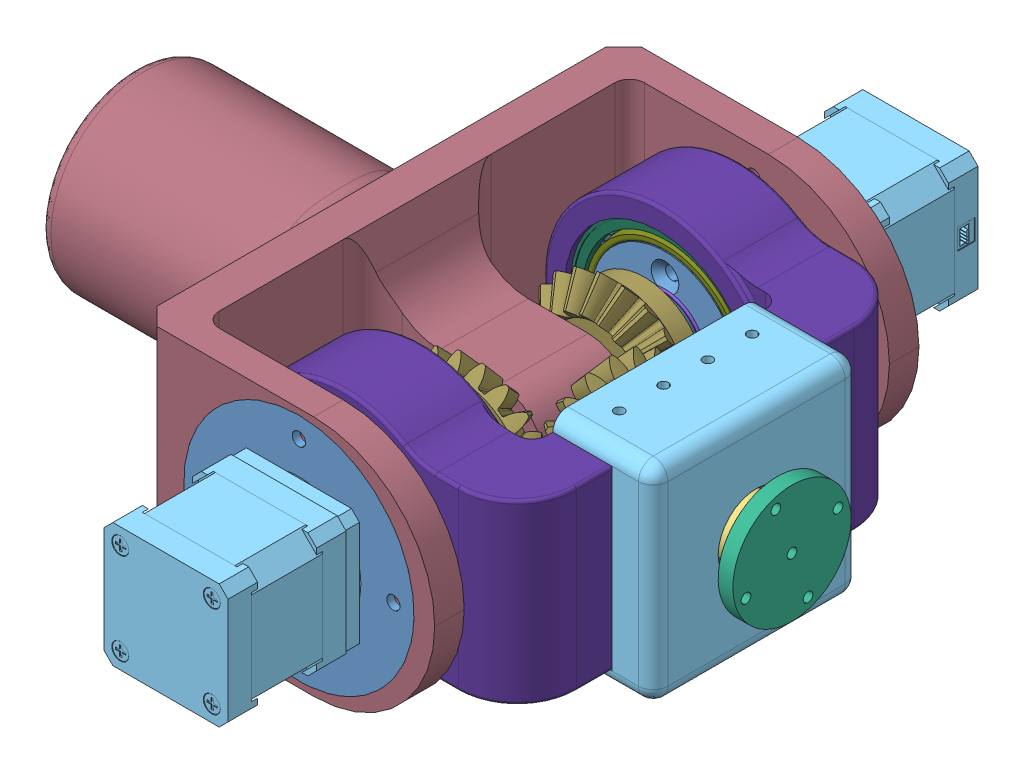
SolidWorks assembly Wrist assembly v3, configuration Default. Lengths in mm.
Overall size (223 82 254).
259 component instances, 28 part files, 61 mates.
Components (placement in the parent):
- Motor sleeve-1: Motor sleeve [Default] at (57.5488 50.2907 113.4481) x (0 0 -1) z (1 0 0) size (40 78 78)
- Motor sleeve-2: Motor sleeve [Default] at (57.5488 50.2907 -50.5519) x (0 0 1) z (-1 0 0) size (40 78 78)
- HK_1412-1: HK_1412 [Default] at (57.5488 50.2907 46.4481) x (0 0 -1) z (0.911021 -0.412359 0) size (12 20 20)
  - HK_1412_3-1: HK_1412_3 [Default] x (1 0 0) z (0 -0.382683 0.92388) size (7.3 2 2)
  - HK_1412_3-2: HK_1412_3 [Default] x (1 0 0) z (0 -0.707107 0.707107) size (7.3 2 2)
  - HK_1412_3-3: HK_1412_3 [Default] x (1 0 0) z (0 -0.92388 0.382683) size (7.3 2 2)
  - HK_1412_3-4: HK_1412_3 [Default] x (1 0 0) z (0 -1 0) size (7.3 2 2)
  - HK_1412_3-5: HK_1412_3 [Default] x (1 0 0) z (0 -0.92388 -0.382683) size (7.3 2 2)
  - HK_1412_3-6: HK_1412_3 [Default] x (1 0 0) z (0 -0.707107 -0.707107) size (7.3 2 2)
  - HK_1412_3-7: HK_1412_3 [Default] x (1 0 0) z (0 -0.382683 -0.92388) size (7.3 2 2)
  - HK_1412_3-8: HK_1412_3 [Default] x (1 0 0) z (0 0 -1) size (7.3 2 2)
  - HK_1412_3-9: HK_1412_3 [Default] x (1 0 0) z (0 0.382683 -0.92388) size (7.3 2 2)
  - HK_1412_3-10: HK_1412_3 [Default] x (1 0 0) z (0 0.707107 -0.707107) size (7.3 2 2)
  - HK_1412_3-11: HK_1412_3 [Default] x (1 0 0) z (0 0.92388 -0.382683) size (7.3 2 2)
  - HK_1412_3-12: HK_1412_3 [Default] x (1 0 0) z (0 1 0) size (7.3 2 2)
  - HK_1412_3-13: HK_1412_3 [Default] x (1 0 0) z (0 0.92388 0.382683) size (7.3 2 2)
  - HK_1412_3-14: HK_1412_3 [Default] x (1 0 0) z (0 0.707107 0.707107) size (7.3 2 2)
  - HK_1412_3-15: HK_1412_3 [Default] x (1 0 0) z (0 0.382683 0.92388) size (7.3 2 2)
  - HK_1412_3-16: HK_1412_3 [Default] at origin size (7.3 2 2)
  - HK_1412_20-1: HK_1412_20 [Default] x (1 0 0) z (0 -0.382683 0.92388) size (7.3 2 2)
  - HK_1412_20-2: HK_1412_20 [Default] x (1 0 0) z (0 -0.707107 0.707107) size (7.3 2 2)
  - HK_1412_20-3: HK_1412_20 [Default] x (1 0 0) z (0 -0.92388 0.382683) size (7.3 2 2)
  - HK_1412_20-4: HK_1412_20 [Default] x (1 0 0) z (0 -1 0) size (7.3 2 2)
  - HK_1412_20-5: HK_1412_20 [Default] x (1 0 0) z (0 -0.92388 -0.382683) size (7.3 2 2)
  - HK_1412_20-6: HK_1412_20 [Default] x (1 0 0) z (0 -0.707107 -0.707107) size (7.3 2 2)
  - HK_1412_20-7: HK_1412_20 [Default] x (1 0 0) z (0 -0.382683 -0.92388) size (7.3 2 2)
  - HK_1412_20-8: HK_1412_20 [Default] x (1 0 0) z (0 0 -1) size (7.3 2 2)
  - HK_1412_20-9: HK_1412_20 [Default] x (1 0 0) z (0 0.382683 -0.92388) size (7.3 2 2)
  - HK_1412_20-10: HK_1412_20 [Default] x (1 0 0) z (0 0.707107 -0.707107) size (7.3 2 2)
  - HK_1412_20-11: HK_1412_20 [Default] x (1 0 0) z (0 0.92388 -0.382683) size (7.3 2 2)
  - HK_1412_20-12: HK_1412_20 [Default] x (1 0 0) z (0 1 0) size (7.3 2 2)
  - HK_1412_20-13: HK_1412_20 [Default] x (1 0 0) z (0 0.92388 0.382683) size (7.3 2 2)
  - HK_1412_20-14: HK_1412_20 [Default] x (1 0 0) z (0 0.707107 0.707107) size (7.3 2 2)
  - HK_1412_20-15: HK_1412_20 [Default] x (1 0 0) z (0 0.382683 0.92388) size (7.3 2 2)
  - HK_1412_20-16: HK_1412_20 [Default] at origin size (7.3 2 2)
  - HK_1412_37-1: HK_1412_37 [Default] at origin size (12 20 20)
- HK_1412-2: HK_1412 [Default] at (57.5488 50.2907 28.4481) x (0 0 -1) z (0.122911 0.992418 0) size (12 20 20)
  - HK_1412_3-1: HK_1412_3 [Default] x (1 0 0) z (0 -0.382683 0.92388) size (7.3 2 2)
  - HK_1412_3-2: HK_1412_3 [Default] x (1 0 0) z (0 -0.707107 0.707107) size (7.3 2 2)
  - HK_1412_3-3: HK_1412_3 [Default] x (1 0 0) z (0 -0.92388 0.382683) size (7.3 2 2)
  - HK_1412_3-4: HK_1412_3 [Default] x (1 0 0) z (0 -1 0) size (7.3 2 2)
  - HK_1412_3-5: HK_1412_3 [Default] x (1 0 0) z (0 -0.92388 -0.382683) size (7.3 2 2)
  - HK_1412_3-6: HK_1412_3 [Default] x (1 0 0) z (0 -0.707107 -0.707107) size (7.3 2 2)
  - HK_1412_3-7: HK_1412_3 [Default] x (1 0 0) z (0 -0.382683 -0.92388) size (7.3 2 2)
  - HK_1412_3-8: HK_1412_3 [Default] x (1 0 0) z (0 0 -1) size (7.3 2 2)
  - HK_1412_3-9: HK_1412_3 [Default] x (1 0 0) z (0 0.382683 -0.92388) size (7.3 2 2)
  - HK_1412_3-10: HK_1412_3 [Default] x (1 0 0) z (0 0.707107 -0.707107) size (7.3 2 2)
  - HK_1412_3-11: HK_1412_3 [Default] x (1 0 0) z (0 0.92388 -0.382683) size (7.3 2 2)
  - HK_1412_3-12: HK_1412_3 [Default] x (1 0 0) z (0 1 0) size (7.3 2 2)
  - HK_1412_3-13: HK_1412_3 [Default] x (1 0 0) z (0 0.92388 0.382683) size (7.3 2 2)
  - HK_1412_3-14: HK_1412_3 [Default] x (1 0 0) z (0 0.707107 0.707107) size (7.3 2 2)
  - HK_1412_3-15: HK_1412_3 [Default] x (1 0 0) z (0 0.382683 0.92388) size (7.3 2 2)
  - HK_1412_3-16: HK_1412_3 [Default] at origin size (7.3 2 2)
  - HK_1412_20-1: HK_1412_20 [Default] x (1 0 0) z (0 -0.382683 0.92388) size (7.3 2 2)
  - HK_1412_20-2: HK_1412_20 [Default] x (1 0 0) z (0 -0.707107 0.707107) size (7.3 2 2)
  - HK_1412_20-3: HK_1412_20 [Default] x (1 0 0) z (0 -0.92388 0.382683) size (7.3 2 2)
  - HK_1412_20-4: HK_1412_20 [Default] x (1 0 0) z (0 -1 0) size (7.3 2 2)
  - HK_1412_20-5: HK_1412_20 [Default] x (1 0 0) z (0 -0.92388 -0.382683) size (7.3 2 2)
  - HK_1412_20-6: HK_1412_20 [Default] x (1 0 0) z (0 -0.707107 -0.707107) size (7.3 2 2)
  - HK_1412_20-7: HK_1412_20 [Default] x (1 0 0) z (0 -0.382683 -0.92388) size (7.3 2 2)
  - HK_1412_20-8: HK_1412_20 [Default] x (1 0 0) z (0 0 -1) size (7.3 2 2)
  - HK_1412_20-9: HK_1412_20 [Default] x (1 0 0) z (0 0.382683 -0.92388) size (7.3 2 2)
  - HK_1412_20-10: HK_1412_20 [Default] x (1 0 0) z (0 0.707107 -0.707107) size (7.3 2 2)
  - HK_1412_20-11: HK_1412_20 [Default] x (1 0 0) z (0 0.92388 -0.382683) size (7.3 2 2)
  - HK_1412_20-12: HK_1412_20 [Default] x (1 0 0) z (0 1 0) size (7.3 2 2)
  - HK_1412_20-13: HK_1412_20 [Default] x (1 0 0) z (0 0.92388 0.382683) size (7.3 2 2)
  - HK_1412_20-14: HK_1412_20 [Default] x (1 0 0) z (0 0.707107 0.707107) size (7.3 2 2)
  - HK_1412_20-15: HK_1412_20 [Default] x (1 0 0) z (0 0.382683 0.92388) size (7.3 2 2)
  - HK_1412_20-16: HK_1412_20 [Default] at origin size (7.3 2 2)
  - HK_1412_37-1: HK_1412_37 [Default] at origin size (12 20 20)
- 17HS15-1684D-HG10-AR3-2: 17HS15-1684D-HG10-AR3 [Default] at (57.5488 50.2907 -55.5519) size (42.88 42 103.5)
- 17HS15-1684D-HG10-AR3-3: 17HS15-1684D-HG10-AR3 [Default] at (57.5488 50.2907 118.4481) x (-1 0 0) z (0 0 -1) size (42.88 42 103.5)
- shaft-1: shaft [Default] at (57.5488 50.2907 -12.0519) x (0 0 1) z (0.017885 0.99984 0) size (42 17 17)
- shaft-2: shaft [Default] at (57.5488 50.2907 74.9481) x (0 0 -1) z (-0.597351 0.80198 0) size (42 17 17)
- AXK_1528___AS_1528___AS_1528-2: AXK_1528___AS_1528___AS_1528 [Default] at (57.5488 50.2907 71.4481) x (0 0 -1) z (0.812919 0.582377 0) size (4 28 28)
  - AXK_1528___AS_1528___AS_1528_3-1: AXK_1528___AS_1528___AS_1528_3 [Default] x (1 0 0) z (0 -0.309017 0.951057) size (2 5 2)
  - AXK_1528___AS_1528___AS_1528_3-2: AXK_1528___AS_1528___AS_1528_3 [Default] x (1 0 0) z (0 -0.587785 0.809017) size (2 5 2)
  - AXK_1528___AS_1528___AS_1528_3-3: AXK_1528___AS_1528___AS_1528_3 [Default] x (1 0 0) z (0 -0.809017 0.587785) size (2 5 2)
  - AXK_1528___AS_1528___AS_1528_3-4: AXK_1528___AS_1528___AS_1528_3 [Default] x (1 0 0) z (0 -0.951057 0.309017) size (2 5 2)
  - AXK_1528___AS_1528___AS_1528_3-5: AXK_1528___AS_1528___AS_1528_3 [Default] x (1 0 0) z (0 -1 0) size (2 5 2)
  - AXK_1528___AS_1528___AS_1528_3-6: AXK_1528___AS_1528___AS_1528_3 [Default] x (1 0 0) z (0 -0.951057 -0.309017) size (2 5 2)
  - AXK_1528___AS_1528___AS_1528_3-7: AXK_1528___AS_1528___AS_1528_3 [Default] x (1 0 0) z (0 -0.809017 -0.587785) size (2 5 2)
  - AXK_1528___AS_1528___AS_1528_3-8: AXK_1528___AS_1528___AS_1528_3 [Default] x (1 0 0) z (0 -0.587785 -0.809017) size (2 5 2)
  - AXK_1528___AS_1528___AS_1528_3-9: AXK_1528___AS_1528___AS_1528_3 [Default] x (1 0 0) z (0 -0.309017 -0.951057) size (2 5 2)
  - AXK_1528___AS_1528___AS_1528_3-10: AXK_1528___AS_1528___AS_1528_3 [Default] x (1 0 0) z (0 0 -1) size (2 5 2)
  - AXK_1528___AS_1528___AS_1528_3-11: AXK_1528___AS_1528___AS_1528_3 [Default] x (1 0 0) z (0 0.309017 -0.951057) size (2 5 2)
  - AXK_1528___AS_1528___AS_1528_3-12: AXK_1528___AS_1528___AS_1528_3 [Default] x (1 0 0) z (0 0.587785 -0.809017) size (2 5 2)
  - AXK_1528___AS_1528___AS_1528_3-13: AXK_1528___AS_1528___AS_1528_3 [Default] x (1 0 0) z (0 0.809017 -0.587785) size (2 5 2)
  - AXK_1528___AS_1528___AS_1528_3-14: AXK_1528___AS_1528___AS_1528_3 [Default] x (1 0 0) z (0 0.951057 -0.309017) size (2 5 2)
  - AXK_1528___AS_1528___AS_1528_3-15: AXK_1528___AS_1528___AS_1528_3 [Default] x (1 0 0) z (0 1 0) size (2 5 2)
  - AXK_1528___AS_1528___AS_1528_3-16: AXK_1528___AS_1528___AS_1528_3 [Default] x (1 0 0) z (0 0.951057 0.309017) size (2 5 2)
  - AXK_1528___AS_1528___AS_1528_3-17: AXK_1528___AS_1528___AS_1528_3 [Default] x (1 0 0) z (0 0.809017 0.587785) size (2 5 2)
  - AXK_1528___AS_1528___AS_1528_3-18: AXK_1528___AS_1528___AS_1528_3 [Default] x (1 0 0) z (0 0.587785 0.809017) size (2 5 2)
  - AXK_1528___AS_1528___AS_1528_3-19: AXK_1528___AS_1528___AS_1528_3 [Default] x (1 0 0) z (0 0.309017 0.951057) size (2 5 2)
  - AXK_1528___AS_1528___AS_1528_3-20: AXK_1528___AS_1528___AS_1528_3 [Default] at origin size (2 5 2)
  - AXK_1528___AS_1528___AS_1528_24-1: AXK_1528___AS_1528___AS_1528_24 [Default] at origin size (1 28 28)
  - AXK_1528___AS_1528___AS_1528_26-1: AXK_1528___AS_1528___AS_1528_26 [Default] at origin size (1 28 28)
  - AXK_1528___AS_1528___AS_1528_28-1: AXK_1528___AS_1528___AS_1528_28 [Default] at origin size (1.6 28 28)
- 2mm spacer-1: 2mm spacer [Default] at (57.5488 50.2907 66.4481) x (0.999741 0.022777 0) z (0 0 1) size (28 28 1.5)
- straight miter gear_am-1: straight miter gear_am [A 1C 4MYKW25020] at (57.5488 50.2907 59.074) x (0 0 -1) z (0.597351 -0.80198 0) size (19.66 53.34 53.34)
- AXK_1528___AS_1528___AS_1528-3: AXK_1528___AS_1528___AS_1528 [Default] at (57.5488 50.2907 -8.5519) x (0 0 -1) z (0.999526 -0.030788 0) size (4 28 28)
  - AXK_1528___AS_1528___AS_1528_3-1: AXK_1528___AS_1528___AS_1528_3 [Default] x (1 0 0) z (0 -0.309017 0.951057) size (2 5 2)
  - AXK_1528___AS_1528___AS_1528_3-2: AXK_1528___AS_1528___AS_1528_3 [Default] x (1 0 0) z (0 -0.587785 0.809017) size (2 5 2)
  - AXK_1528___AS_1528___AS_1528_3-3: AXK_1528___AS_1528___AS_1528_3 [Default] x (1 0 0) z (0 -0.809017 0.587785) size (2 5 2)
  - AXK_1528___AS_1528___AS_1528_3-4: AXK_1528___AS_1528___AS_1528_3 [Default] x (1 0 0) z (0 -0.951057 0.309017) size (2 5 2)
  - AXK_1528___AS_1528___AS_1528_3-5: AXK_1528___AS_1528___AS_1528_3 [Default] x (1 0 0) z (0 -1 0) size (2 5 2)
  - AXK_1528___AS_1528___AS_1528_3-6: AXK_1528___AS_1528___AS_1528_3 [Default] x (1 0 0) z (0 -0.951057 -0.309017) size (2 5 2)
  - AXK_1528___AS_1528___AS_1528_3-7: AXK_1528___AS_1528___AS_1528_3 [Default] x (1 0 0) z (0 -0.809017 -0.587785) size (2 5 2)
  - AXK_1528___AS_1528___AS_1528_3-8: AXK_1528___AS_1528___AS_1528_3 [Default] x (1 0 0) z (0 -0.587785 -0.809017) size (2 5 2)
  - AXK_1528___AS_1528___AS_1528_3-9: AXK_1528___AS_1528___AS_1528_3 [Default] x (1 0 0) z (0 -0.309017 -0.951057) size (2 5 2)
  - AXK_1528___AS_1528___AS_1528_3-10: AXK_1528___AS_1528___AS_1528_3 [Default] x (1 0 0) z (0 0 -1) size (2 5 2)
  - AXK_1528___AS_1528___AS_1528_3-11: AXK_1528___AS_1528___AS_1528_3 [Default] x (1 0 0) z (0 0.309017 -0.951057) size (2 5 2)
  - AXK_1528___AS_1528___AS_1528_3-12: AXK_1528___AS_1528___AS_1528_3 [Default] x (1 0 0) z (0 0.587785 -0.809017) size (2 5 2)
  - AXK_1528___AS_1528___AS_1528_3-13: AXK_1528___AS_1528___AS_1528_3 [Default] x (1 0 0) z (0 0.809017 -0.587785) size (2 5 2)
  - AXK_1528___AS_1528___AS_1528_3-14: AXK_1528___AS_1528___AS_1528_3 [Default] x (1 0 0) z (0 0.951057 -0.309017) size (2 5 2)
  - AXK_1528___AS_1528___AS_1528_3-15: AXK_1528___AS_1528___AS_1528_3 [Default] x (1 0 0) z (0 1 0) size (2 5 2)
  - AXK_1528___AS_1528___AS_1528_3-16: AXK_1528___AS_1528___AS_1528_3 [Default] x (1 0 0) z (0 0.951057 0.309017) size (2 5 2)
  - AXK_1528___AS_1528___AS_1528_3-17: AXK_1528___AS_1528___AS_1528_3 [Default] x (1 0 0) z (0 0.809017 0.587785) size (2 5 2)
  - AXK_1528___AS_1528___AS_1528_3-18: AXK_1528___AS_1528___AS_1528_3 [Default] x (1 0 0) z (0 0.587785 0.809017) size (2 5 2)
  - AXK_1528___AS_1528___AS_1528_3-19: AXK_1528___AS_1528___AS_1528_3 [Default] x (1 0 0) z (0 0.309017 0.951057) size (2 5 2)
  - AXK_1528___AS_1528___AS_1528_3-20: AXK_1528___AS_1528___AS_1528_3 [Default] at origin size (2 5 2)
  - AXK_1528___AS_1528___AS_1528_24-1: AXK_1528___AS_1528___AS_1528_24 [Default] at origin size (1 28 28)
  - AXK_1528___AS_1528___AS_1528_26-1: AXK_1528___AS_1528___AS_1528_26 [Default] at origin size (1 28 28)
  - AXK_1528___AS_1528___AS_1528_28-1: AXK_1528___AS_1528___AS_1528_28 [Default] at origin size (1.6 28 28)
- 2mm spacer-2: 2mm spacer [Default] at (57.5488 50.2907 -5.0519) x (0.999526 -0.030788 0) z (0 0 1) size (28 28 1.5)
- straight miter gear_am-2: straight miter gear_am [A 1C 4MYKW25020] at (57.5488 50.2907 3.8222) x (0 0 1) z (-0.017885 -0.99984 0) size (19.66 53.34 53.34)
- Wrist input frame_combined-2: Wrist input frame_combined [Default] at (-20.9706 -62.2225 152.6176) x (-1 0 0) z (0 0 -1) size (184 82 164)
- NKI_50_25-1: NKI_50_25 [Default] at (57.5488 50.2907 -10.5519) x (0 0 -1) z (0.995738 -0.092229 0) size (25 68.42 68)
  - NKI_50_25_37-1: NKI_50_25_37 [Default] x (1 0 0) z (0 -0.189251 0.981929) size (18.8 3.5 3.5)
  - NKI_50_25_37-2: NKI_50_25_37 [Default] x (1 0 0) z (0 -0.371662 0.928368) size (18.8 3.5 3.5)
  - NKI_50_25_37-3: NKI_50_25_37 [Default] x (1 0 0) z (0 -0.540641 0.841254) size (18.8 3.5 3.5)
  - NKI_50_25_37-4: NKI_50_25_37 [Default] x (1 0 0) z (0 -0.690079 0.723734) size (18.8 3.5 3.5)
  - NKI_50_25_37-5: NKI_50_25_37 [Default] x (1 0 0) z (0 -0.814576 0.580057) size (18.8 3.5 3.5)
  - NKI_50_25_37-6: NKI_50_25_37 [Default] x (1 0 0) z (0 -0.909632 0.415415) size (18.8 3.5 3.5)
  - NKI_50_25_37-7: NKI_50_25_37 [Default] x (1 0 0) z (0 -0.971812 0.235759) size (18.8 3.5 3.5)
  - NKI_50_25_37-8: NKI_50_25_37 [Default] x (1 0 0) z (0 -0.998867 0.047582) size (18.8 3.5 3.5)
  - NKI_50_25_37-9: NKI_50_25_37 [Default] x (1 0 0) z (0 -0.989821 -0.142315) size (18.8 3.5 3.5)
  - NKI_50_25_37-10: NKI_50_25_37 [Default] x (1 0 0) z (0 -0.945001 -0.327068) size (18.8 3.5 3.5)
  - NKI_50_25_37-11: NKI_50_25_37 [Default] x (1 0 0) z (0 -0.866025 -0.5) size (18.8 3.5 3.5)
  - NKI_50_25_37-12: NKI_50_25_37 [Default] x (1 0 0) z (0 -0.75575 -0.654861) size (18.8 3.5 3.5)
  - NKI_50_25_37-13: NKI_50_25_37 [Default] x (1 0 0) z (0 -0.618159 -0.786053) size (18.8 3.5 3.5)
  - NKI_50_25_37-14: NKI_50_25_37 [Default] x (1 0 0) z (0 -0.458227 -0.888835) size (18.8 3.5 3.5)
  - NKI_50_25_37-15: NKI_50_25_37 [Default] x (1 0 0) z (0 -0.281733 -0.959493) size (18.8 3.5 3.5)
  - NKI_50_25_37-16: NKI_50_25_37 [Default] x (1 0 0) z (0 -0.095056 -0.995472) size (18.8 3.5 3.5)
  - NKI_50_25_37-17: NKI_50_25_37 [Default] x (1 0 0) z (0 0.095056 -0.995472) size (18.8 3.5 3.5)
  - NKI_50_25_37-18: NKI_50_25_37 [Default] x (1 0 0) z (0 0.281733 -0.959493) size (18.8 3.5 3.5)
  - NKI_50_25_37-19: NKI_50_25_37 [Default] x (1 0 0) z (0 0.458227 -0.888835) size (18.8 3.5 3.5)
  - NKI_50_25_37-20: NKI_50_25_37 [Default] x (1 0 0) z (0 0.618159 -0.786053) size (18.8 3.5 3.5)
  - NKI_50_25_37-21: NKI_50_25_37 [Default] x (1 0 0) z (0 0.75575 -0.654861) size (18.8 3.5 3.5)
  - NKI_50_25_37-22: NKI_50_25_37 [Default] x (1 0 0) z (0 0.866025 -0.5) size (18.8 3.5 3.5)
  - NKI_50_25_37-23: NKI_50_25_37 [Default] x (1 0 0) z (0 0.945001 -0.327068) size (18.8 3.5 3.5)
  - NKI_50_25_37-24: NKI_50_25_37 [Default] x (1 0 0) z (0 0.989821 -0.142315) size (18.8 3.5 3.5)
  - NKI_50_25_37-25: NKI_50_25_37 [Default] x (1 0 0) z (0 0.998867 0.047582) size (18.8 3.5 3.5)
  - NKI_50_25_37-26: NKI_50_25_37 [Default] x (1 0 0) z (0 0.971812 0.235759) size (18.8 3.5 3.5)
  - NKI_50_25_37-27: NKI_50_25_37 [Default] x (1 0 0) z (0 0.909632 0.415415) size (18.8 3.5 3.5)
  - NKI_50_25_37-28: NKI_50_25_37 [Default] x (1 0 0) z (0 0.814576 0.580057) size (18.8 3.5 3.5)
  - NKI_50_25_37-29: NKI_50_25_37 [Default] x (1 0 0) z (0 0.690079 0.723734) size (18.8 3.5 3.5)
  - NKI_50_25_37-30: NKI_50_25_37 [Default] x (1 0 0) z (0 0.540641 0.841254) size (18.8 3.5 3.5)
  - NKI_50_25_37-31: NKI_50_25_37 [Default] x (1 0 0) z (0 0.371662 0.928368) size (18.8 3.5 3.5)
  - NKI_50_25_37-32: NKI_50_25_37 [Default] x (1 0 0) z (0 0.189251 0.981929) size (18.8 3.5 3.5)
  - NKI_50_25_37-33: NKI_50_25_37 [Default] at origin size (18.8 3.5 3.5)
  - NKI_50_25_71-1: NKI_50_25_71 [Default] at origin size (25 68.42 68)
  - NKI_50_25_73-1: NKI_50_25_73 [Default] at origin size (25 55 55)
- NKI_50_25-2: NKI_50_25 [Default] at (57.5488 50.2907 98.4481) x (0 0 -1) z (0.982967 -0.183783 0) size (25 68.42 68)
  - NKI_50_25_37-1: NKI_50_25_37 [Default] x (1 0 0) z (0 -0.189251 0.981929) size (18.8 3.5 3.5)
  - NKI_50_25_37-2: NKI_50_25_37 [Default] x (1 0 0) z (0 -0.371662 0.928368) size (18.8 3.5 3.5)
  - NKI_50_25_37-3: NKI_50_25_37 [Default] x (1 0 0) z (0 -0.540641 0.841254) size (18.8 3.5 3.5)
  - NKI_50_25_37-4: NKI_50_25_37 [Default] x (1 0 0) z (0 -0.690079 0.723734) size (18.8 3.5 3.5)
  - NKI_50_25_37-5: NKI_50_25_37 [Default] x (1 0 0) z (0 -0.814576 0.580057) size (18.8 3.5 3.5)
  - NKI_50_25_37-6: NKI_50_25_37 [Default] x (1 0 0) z (0 -0.909632 0.415415) size (18.8 3.5 3.5)
  - NKI_50_25_37-7: NKI_50_25_37 [Default] x (1 0 0) z (0 -0.971812 0.235759) size (18.8 3.5 3.5)
  - NKI_50_25_37-8: NKI_50_25_37 [Default] x (1 0 0) z (0 -0.998867 0.047582) size (18.8 3.5 3.5)
  - NKI_50_25_37-9: NKI_50_25_37 [Default] x (1 0 0) z (0 -0.989821 -0.142315) size (18.8 3.5 3.5)
  - NKI_50_25_37-10: NKI_50_25_37 [Default] x (1 0 0) z (0 -0.945001 -0.327068) size (18.8 3.5 3.5)
  - NKI_50_25_37-11: NKI_50_25_37 [Default] x (1 0 0) z (0 -0.866025 -0.5) size (18.8 3.5 3.5)
  - NKI_50_25_37-12: NKI_50_25_37 [Default] x (1 0 0) z (0 -0.75575 -0.654861) size (18.8 3.5 3.5)
  - NKI_50_25_37-13: NKI_50_25_37 [Default] x (1 0 0) z (0 -0.618159 -0.786053) size (18.8 3.5 3.5)
  - NKI_50_25_37-14: NKI_50_25_37 [Default] x (1 0 0) z (0 -0.458227 -0.888835) size (18.8 3.5 3.5)
  - NKI_50_25_37-15: NKI_50_25_37 [Default] x (1 0 0) z (0 -0.281733 -0.959493) size (18.8 3.5 3.5)
  - NKI_50_25_37-16: NKI_50_25_37 [Default] x (1 0 0) z (0 -0.095056 -0.995472) size (18.8 3.5 3.5)
  - NKI_50_25_37-17: NKI_50_25_37 [Default] x (1 0 0) z (0 0.095056 -0.995472) size (18.8 3.5 3.5)
  - NKI_50_25_37-18: NKI_50_25_37 [Default] x (1 0 0) z (0 0.281733 -0.959493) size (18.8 3.5 3.5)
  - NKI_50_25_37-19: NKI_50_25_37 [Default] x (1 0 0) z (0 0.458227 -0.888835) size (18.8 3.5 3.5)
  - NKI_50_25_37-20: NKI_50_25_37 [Default] x (1 0 0) z (0 0.618159 -0.786053) size (18.8 3.5 3.5)
  - NKI_50_25_37-21: NKI_50_25_37 [Default] x (1 0 0) z (0 0.75575 -0.654861) size (18.8 3.5 3.5)
  - NKI_50_25_37-22: NKI_50_25_37 [Default] x (1 0 0) z (0 0.866025 -0.5) size (18.8 3.5 3.5)
  - NKI_50_25_37-23: NKI_50_25_37 [Default] x (1 0 0) z (0 0.945001 -0.327068) size (18.8 3.5 3.5)
  - NKI_50_25_37-24: NKI_50_25_37 [Default] x (1 0 0) z (0 0.989821 -0.142315) size (18.8 3.5 3.5)
  - NKI_50_25_37-25: NKI_50_25_37 [Default] x (1 0 0) z (0 0.998867 0.047582) size (18.8 3.5 3.5)
  - NKI_50_25_37-26: NKI_50_25_37 [Default] x (1 0 0) z (0 0.971812 0.235759) size (18.8 3.5 3.5)
  - NKI_50_25_37-27: NKI_50_25_37 [Default] x (1 0 0) z (0 0.909632 0.415415) size (18.8 3.5 3.5)
  - NKI_50_25_37-28: NKI_50_25_37 [Default] x (1 0 0) z (0 0.814576 0.580057) size (18.8 3.5 3.5)
  - NKI_50_25_37-29: NKI_50_25_37 [Default] x (1 0 0) z (0 0.690079 0.723734) size (18.8 3.5 3.5)
  - NKI_50_25_37-30: NKI_50_25_37 [Default] x (1 0 0) z (0 0.540641 0.841254) size (18.8 3.5 3.5)
  - NKI_50_25_37-31: NKI_50_25_37 [Default] x (1 0 0) z (0 0.371662 0.928368) size (18.8 3.5 3.5)
  - NKI_50_25_37-32: NKI_50_25_37 [Default] x (1 0 0) z (0 0.189251 0.981929) size (18.8 3.5 3.5)
  - NKI_50_25_37-33: NKI_50_25_37 [Default] at origin size (18.8 3.5 3.5)
  - NKI_50_25_71-1: NKI_50_25_71 [Default] at origin size (25 68.42 68)
  - NKI_50_25_73-1: NKI_50_25_73 [Default] at origin size (25 55 55)
- Wrist output frame-1: Wrist output frame [Default] at (57.5488 50.2907 98.4481) x (0 0 -1) z (0 -1 0) size (134 102 78)
- 7203_BEY-3: 7203_BEY [Default] at (108.5488 50.2907 31.4481) x (-1 0 0) z (0 -0.984874 -0.173274) size (12 40 40)
  - 7203_BEY_3-1: 7203_BEY_3 [Default] x (1 0 0) z (0 -0.587785 0.809017) size (7.14 7.14 7.14)
  - 7203_BEY_3-2: 7203_BEY_3 [Default] x (1 0 0) z (0 -0.951057 0.309017) size (7.14 7.14 7.14)
  - 7203_BEY_3-3: 7203_BEY_3 [Default] x (1 0 0) z (0 -0.951057 -0.309017) size (7.14 7.14 7.14)
  - 7203_BEY_3-4: 7203_BEY_3 [Default] x (1 0 0) z (0 -0.587785 -0.809017) size (7.14 7.14 7.14)
  - 7203_BEY_3-5: 7203_BEY_3 [Default] x (1 0 0) z (0 0 -1) size (7.14 7.14 7.14)
  - 7203_BEY_3-6: 7203_BEY_3 [Default] x (1 0 0) z (0 0.587785 -0.809017) size (7.14 7.14 7.14)
  - 7203_BEY_3-7: 7203_BEY_3 [Default] x (1 0 0) z (0 0.951057 -0.309017) size (7.14 7.14 7.14)
  - 7203_BEY_3-8: 7203_BEY_3 [Default] x (1 0 0) z (0 0.951057 0.309017) size (7.14 7.14 7.14)
  - 7203_BEY_3-9: 7203_BEY_3 [Default] x (1 0 0) z (0 0.587785 0.809017) size (7.14 7.14 7.14)
  - 7203_BEY_3-10: 7203_BEY_3 [Default] at origin size (7.14 7.14 7.14)
  - 7203_BEY_14-1: 7203_BEY_14 [Default] at origin size (12 40 40)
  - 7203_BEY_16-1: 7203_BEY_16 [Default] at origin size (12 26.25 26.25)
- 7203_BEY-4: 7203_BEY [Default] at (108.5488 50.2907 31.4481) x (1 0 0) z (0 0.327595 0.944818) size (12 40 40)
  - 7203_BEY_3-1: 7203_BEY_3 [Default] x (1 0 0) z (0 -0.587785 0.809017) size (7.14 7.14 7.14)
  - 7203_BEY_3-2: 7203_BEY_3 [Default] x (1 0 0) z (0 -0.951057 0.309017) size (7.14 7.14 7.14)
  - 7203_BEY_3-3: 7203_BEY_3 [Default] x (1 0 0) z (0 -0.951057 -0.309017) size (7.14 7.14 7.14)
  - 7203_BEY_3-4: 7203_BEY_3 [Default] x (1 0 0) z (0 -0.587785 -0.809017) size (7.14 7.14 7.14)
  - 7203_BEY_3-5: 7203_BEY_3 [Default] x (1 0 0) z (0 0 -1) size (7.14 7.14 7.14)
  - 7203_BEY_3-6: 7203_BEY_3 [Default] x (1 0 0) z (0 0.587785 -0.809017) size (7.14 7.14 7.14)
  - 7203_BEY_3-7: 7203_BEY_3 [Default] x (1 0 0) z (0 0.951057 -0.309017) size (7.14 7.14 7.14)
  - 7203_BEY_3-8: 7203_BEY_3 [Default] x (1 0 0) z (0 0.951057 0.309017) size (7.14 7.14 7.14)
  - 7203_BEY_3-9: 7203_BEY_3 [Default] x (1 0 0) z (0 0.587785 0.809017) size (7.14 7.14 7.14)
  - 7203_BEY_3-10: 7203_BEY_3 [Default] at origin size (7.14 7.14 7.14)
  - 7203_BEY_14-1: 7203_BEY_14 [Default] at origin size (12 40 40)
  - 7203_BEY_16-1: 7203_BEY_16 [Default] at origin size (12 26.25 26.25)
- Output shaft-1: Output shaft [Default] at (75.5488 50.2907 31.4481) x (0 0.330033 -0.94397) z (1 0 0) size (22.5 22.5 62)
- 4mm spacer-1: 4mm spacer [Default] at (92.5488 50.2907 31.4481) x (0 -0.609252 -0.792977) z (1 0 0) size (26 26 4)
- straight miter gear_am-3: straight miter gear_am [A 1C 4MYKW25020] at (85.1747 50.2907 31.4481) x (-1 0 0) z (0 -0.883146 0.469098) size (19.66 53.34 53.34)
- End effector mounting fixture-2: End effector mounting fixture [Default] at (96.5488 50.2907 -3.5519) size (34 70 70)
- End effector mount-1: End effector mount [Default] at (132.5488 50.2907 31.4481) x (0 -0.330033 0.94397) z (1 0 0) size (40 40 10)
- AXK_2035___AS_2035___AS_2035-1: AXK_2035___AS_2035___AS_2035 [Default] at (124.5488 50.2907 31.4481) x (1 0 0) z (0 -0.248514 0.968628) size (4 35 35)
  - AXK_2035___AS_2035___AS_2035_3-1: AXK_2035___AS_2035___AS_2035_3 [Default] x (1 0 0) z (0 -0.258819 0.965926) size (2 6 2)
  - AXK_2035___AS_2035___AS_2035_3-2: AXK_2035___AS_2035___AS_2035_3 [Default] x (1 0 0) z (0 -0.5 0.866025) size (2 6 2)
  - AXK_2035___AS_2035___AS_2035_3-3: AXK_2035___AS_2035___AS_2035_3 [Default] x (1 0 0) z (0 -0.707107 0.707107) size (2 6 2)
  - AXK_2035___AS_2035___AS_2035_3-4: AXK_2035___AS_2035___AS_2035_3 [Default] x (1 0 0) z (0 -0.866025 0.5) size (2 6 2)
  - AXK_2035___AS_2035___AS_2035_3-5: AXK_2035___AS_2035___AS_2035_3 [Default] x (1 0 0) z (0 -0.965926 0.258819) size (2 6 2)
  - AXK_2035___AS_2035___AS_2035_3-6: AXK_2035___AS_2035___AS_2035_3 [Default] x (1 0 0) z (0 -1 0) size (2 6 2)
  - AXK_2035___AS_2035___AS_2035_3-7: AXK_2035___AS_2035___AS_2035_3 [Default] x (1 0 0) z (0 -0.965926 -0.258819) size (2 6 2)
  - AXK_2035___AS_2035___AS_2035_3-8: AXK_2035___AS_2035___AS_2035_3 [Default] x (1 0 0) z (0 -0.866025 -0.5) size (2 6 2)
  - AXK_2035___AS_2035___AS_2035_3-9: AXK_2035___AS_2035___AS_2035_3 [Default] x (1 0 0) z (0 -0.707107 -0.707107) size (2 6 2)
  - AXK_2035___AS_2035___AS_2035_3-10: AXK_2035___AS_2035___AS_2035_3 [Default] x (1 0 0) z (0 -0.5 -0.866025) size (2 6 2)
  - AXK_2035___AS_2035___AS_2035_3-11: AXK_2035___AS_2035___AS_2035_3 [Default] x (1 0 0) z (0 -0.258819 -0.965926) size (2 6 2)
  - AXK_2035___AS_2035___AS_2035_3-12: AXK_2035___AS_2035___AS_2035_3 [Default] x (1 0 0) z (0 0 -1) size (2 6 2)
  - AXK_2035___AS_2035___AS_2035_3-13: AXK_2035___AS_2035___AS_2035_3 [Default] x (1 0 0) z (0 0.258819 -0.965926) size (2 6 2)
  - AXK_2035___AS_2035___AS_2035_3-14: AXK_2035___AS_2035___AS_2035_3 [Default] x (1 0 0) z (0 0.5 -0.866025) size (2 6 2)
  - AXK_2035___AS_2035___AS_2035_3-15: AXK_2035___AS_2035___AS_2035_3 [Default] x (1 0 0) z (0 0.707107 -0.707107) size (2 6 2)
  - AXK_2035___AS_2035___AS_2035_3-16: AXK_2035___AS_2035___AS_2035_3 [Default] x (1 0 0) z (0 0.866025 -0.5) size (2 6 2)
  - AXK_2035___AS_2035___AS_2035_3-17: AXK_2035___AS_2035___AS_2035_3 [Default] x (1 0 0) z (0 0.965926 -0.258819) size (2 6 2)
  - AXK_2035___AS_2035___AS_2035_3-18: AXK_2035___AS_2035___AS_2035_3 [Default] x (1 0 0) z (0 1 0) size (2 6 2)
  - AXK_2035___AS_2035___AS_2035_3-19: AXK_2035___AS_2035___AS_2035_3 [Default] x (1 0 0) z (0 0.965926 0.258819) size (2 6 2)
  - AXK_2035___AS_2035___AS_2035_3-20: AXK_2035___AS_2035___AS_2035_3 [Default] x (1 0 0) z (0 0.866025 0.5) size (2 6 2)
  - AXK_2035___AS_2035___AS_2035_3-21: AXK_2035___AS_2035___AS_2035_3 [Default] x (1 0 0) z (0 0.707107 0.707107) size (2 6 2)
  - AXK_2035___AS_2035___AS_2035_3-22: AXK_2035___AS_2035___AS_2035_3 [Default] x (1 0 0) z (0 0.5 0.866025) size (2 6 2)
  - AXK_2035___AS_2035___AS_2035_3-23: AXK_2035___AS_2035___AS_2035_3 [Default] x (1 0 0) z (0 0.258819 0.965926) size (2 6 2)
  - AXK_2035___AS_2035___AS_2035_3-24: AXK_2035___AS_2035___AS_2035_3 [Default] at origin size (2 6 2)
  - AXK_2035___AS_2035___AS_2035_28-1: AXK_2035___AS_2035___AS_2035_28 [Default] at origin size (1 35 35)
  - AXK_2035___AS_2035___AS_2035_30-1: AXK_2035___AS_2035___AS_2035_30 [Default] at origin size (1 35 35)
  - AXK_2035___AS_2035___AS_2035_32-1: AXK_2035___AS_2035___AS_2035_32 [Default] at origin size (1.6 35 35)
Mates (geometry in assembly coordinates):
- Concentric10: concentric aligned: cylinder of Motor sleeve-2 through (57.5488 50.2907 -114.6552) axis (0 0 -1) radius 21; cylinder of 17HS15-1684D-HG10-AR3-2 through (57.5488 50.2907 -15.5519) axis (0 0 -1) radius 21
- Concentric11: concentric aligned: cylinder of Motor sleeve-2 through (57.5488 67.7907 -10.5519) axis (0 0 1) radius 2.25; cylinder of 17HS15-1684D-HG10-AR3-2 through (57.5488 67.7907 -15.5519) axis (0 0 1) radius 2.25
- Concentric13: concentric aligned: cylinder of Motor sleeve-1 through (57.5488 50.2907 177.5515) axis (0 0 1) radius 21; cylinder of 17HS15-1684D-HG10-AR3-3 through (57.5488 50.2907 78.4481) axis (0 0 1) radius 21
- Concentric16: concentric aligned: cylinder of Motor sleeve-1 through (57.5488 67.7907 73.4481) axis (0 0 -1) radius 2.25; circle of 17HS15-1684D-HG10-AR3-3
- Coincident5: coincident anti-aligned: plane of Motor sleeve-2 through (57.5488 71.2907 -15.5519) normal (0 0 -1); plane of 17HS15-1684D-HG10-AR3-2 through (57.5488 50.2907 -15.5519) normal (0 0 1)
- Coincident7: coincident anti-aligned: plane of Motor sleeve-1 through (57.5488 71.2907 78.4481) normal (0 0 1); plane of 17HS15-1684D-HG10-AR3-3 through (57.5488 50.2907 78.4481) normal (0 0 -1)
- Concentric17: concentric aligned: cylinder of 17HS15-1684D-HG10-AR3-2 through (57.5488 50.2907 -8.2519) axis (0 0 -1) radius 4; cylinder of shaft-1 through (57.5488 50.2907 29.9481) axis (0 0 -1) radius 4
- Distance2: distance = 1.5 mm anti-aligned: plane of 17HS15-1684D-HG10-AR3-2 through (57.5488 50.2907 -13.5519) normal (0 0 1); plane of shaft-1 through (57.5488 50.2907 -12.0519) normal (0 0 -1)
- Concentric18: concentric aligned: cylinder of 17HS15-1684D-HG10-AR3-3 through (57.5488 50.2907 71.1481) axis (0 0 1) radius 4; cylinder of shaft-2 through (57.5488 50.2907 32.9481) axis (0 0 1) radius 4
- Distance3: distance = 1.5 mm anti-aligned: plane of 17HS15-1684D-HG10-AR3-3 through (57.5488 50.2907 76.4481) normal (0 0 -1); plane of shaft-2 through (57.5488 50.2907 74.9481) normal (0 0 1)
- Concentric20: concentric anti-aligned: cylinder of shaft-2 through (57.5488 50.2907 69.9481) axis (0 0 1) radius 7.5; circle of AXK_1528___AS_1528___AS_1528-2/AXK_1528___AS_1528___AS_1528_24-1
- Coincident10: coincident anti-aligned: plane of Motor sleeve-1 through (57.5488 58.7907 73.4481) normal (0 0 -1); plane of AXK_1528___AS_1528___AS_1528-2/AXK_1528___AS_1528___AS_1528_26-1 through (49.3956 61.6715 73.4481) normal (0 0 1)
- Concentric21: concentric anti-aligned: cylinder of shaft-2 through (57.5488 50.2907 32.9481) axis (0 0 1) radius 7.5; cylinder of 2mm spacer-1 through (57.5488 50.2907 67.9481) axis (0 0 -1) radius 7
- Coincident11: coincident anti-aligned: plane of shaft-2 through (57.5488 50.2907 67.9481) normal (0 0 -1); plane of 2mm spacer-1 through (57.5488 50.2907 67.9481) normal (0 0 1)
- Concentric22: concentric aligned: cylinder of shaft-2 through (57.5488 50.2907 32.9481) axis (0 0 1) radius 7.5; cylinder of straight miter gear_am-1 through (57.5488 50.2907 24.074) axis (0 0 1) radius 7
- Parallel2: parallel anti-aligned: plane of shaft-2 through (61.4647 55.0777 65.9481) normal (0.80198 0.597351 0); plane of straight miter gear_am-1 through (66.5006 53.8411 24.074) normal (-0.80198 -0.597351 0)
- Coincident13: coincident anti-aligned: plane of 2mm spacer-1 through (57.5488 50.2907 66.4481) normal (0 0 -1); plane of straight miter gear_am-1 through (57.5488 50.2907 66.4481) normal (0 0 1)
- Concentric23: concentric anti-aligned: cylinder of shaft-1 through (57.5488 50.2907 -7.0519) axis (0 0 -1) radius 7.5; cylinder of AXK_1528___AS_1528___AS_1528-3/AXK_1528___AS_1528___AS_1528_28-1 through (57.5488 50.2907 -9.3519) axis (0 0 1) radius 7.5
- Coincident14: coincident anti-aligned: plane of Motor sleeve-2 through (57.5488 58.7907 -10.5519) normal (0 0 1); plane of AXK_1528___AS_1528___AS_1528-3/AXK_1528___AS_1528___AS_1528_24-1 through (57.7797 57.7871 -10.5519) normal (0 0 -1)
- Concentric241: concentric aligned: cylinder of shaft-1 through (57.5488 50.2907 29.9481) axis (0 0 -1) radius 7.5; cylinder of 2mm spacer-2 through (57.5488 50.2907 -3.5519) axis (0 0 -1) radius 14
- Coincident15: coincident anti-aligned: plane of shaft-1 through (57.5488 50.2907 -5.0519) normal (0 0 1); plane of 2mm spacer-2 through (57.5488 50.2907 -5.0519) normal (0 0 -1)
- Concentric25: concentric aligned: cylinder of shaft-1 through (57.5488 50.2907 29.9481) axis (0 0 -1) radius 7.5; cylinder of straight miter gear_am-2 through (57.5488 50.2907 38.8222) axis (0 0 -1) radius 7
- Parallel3: parallel anti-aligned: plane of shaft-1 through (51.5766 51.8977 -3.0519) normal (-0.99984 0.017885 0); plane of straight miter gear_am-2 through (48.2056 47.9574 38.8222) normal (0.99984 -0.017885 0)
- Coincident16: coincident anti-aligned: plane of 2mm spacer-2 through (57.5488 50.2907 -3.5519) normal (0 0 1); plane of straight miter gear_am-2 through (57.5488 50.2907 -3.5519) normal (0 0 -1)
- Concentric242: concentric aligned: cylinder of Motor sleeve-1 through (57.5488 50.2907 177.5515) axis (0 0 1) radius 25; cylinder of Wrist input frame_combined-2 through (57.5488 50.2907 34.4481) axis (0 0 1) radius 10
- Coincident17: coincident anti-aligned: plane of Motor sleeve-2 through (57.5488 76.2907 -48.0519) normal (0 0 1); plane of Wrist input frame_combined-2 through (57.5488 50.2907 -48.0519) normal (0 0 -1)
- Concentric243: concentric anti-aligned: cylinder of Motor sleeve-2 through (57.5488 50.2907 -114.6552) axis (0 0 -1) radius 25; circle of Wrist input frame_combined-2
- Concentric244: concentric aligned: cylinder of HK_1412-2/HK_1412_37-1 through (57.5488 50.2907 -21.5519) axis (0 0 -1) radius 7.5; cylinder of Wrist input frame_combined-2 through (57.5488 50.2907 28.4481) axis (0 0 -1) radius 10
- Coincident18: coincident anti-aligned: plane of HK_1412-2/HK_1412_37-1 through (48.4186 51.4215 28.4481) normal (0 0 1); plane of Wrist input frame_combined-2 through (57.5488 50.2907 28.4481) normal (0 0 -1)
- Concentric245: concentric anti-aligned: cylinder of HK_1412-1/HK_1412_37-1 through (57.5488 50.2907 -3.5519) axis (0 0 -1) radius 10; cylinder of Wrist input frame_combined-2 through (57.5488 50.2907 34.4481) axis (0 0 1) radius 10
- Coincident19: coincident anti-aligned: plane of HK_1412-1/HK_1412_37-1 through (60.6415 57.1233 34.4481) normal (0 0 -1); plane of Wrist input frame_combined-2 through (57.5488 50.2907 34.4481) normal (0 0 1)
- Concentric246: concentric anti-aligned: circle of Motor sleeve-2; circle of Wrist input frame_combined-2
- Concentric247: concentric anti-aligned: cylinder of Motor sleeve-1 through (57.5488 82.2907 113.4481) axis (0 0 1) radius 2.25; circle of Wrist input frame_combined-2
- Coincident20: coincident anti-aligned: plane of Motor sleeve-1 through (57.5488 76.2907 110.9481) normal (0 0 -1); plane of Wrist input frame_combined-2 through (57.5488 50.2907 110.9481) normal (0 0 1)
- Concentric248: concentric aligned: cylinder of Motor sleeve-2 through (57.5488 50.2907 -114.6552) axis (0 0 -1) radius 25; cylinder of NKI_50_25-1/NKI_50_25_73-1 through (57.5488 50.2907 -35.5519) axis (0 0 -1) radius 25
- Distance4: distance = 0 mm anti-aligned: plane of Motor sleeve-2 through (57.5488 75.2907 -35.5519) normal (0 0 1); plane of NKI_50_25-1/NKI_50_25_73-1 through (59.9099 75.7816 -35.5519) normal (0 0 -1)
- Concentric249: concentric anti-aligned: cylinder of Motor sleeve-1 through (57.5488 50.2907 177.5515) axis (0 0 1) radius 25; cylinder of NKI_50_25-2/NKI_50_25_73-1 through (57.5488 50.2907 73.4481) axis (0 0 -1) radius 25
- Distance5: distance = 0 mm anti-aligned: plane of Motor sleeve-1 through (57.5488 75.2907 98.4481) normal (0 0 -1); plane of NKI_50_25-2/NKI_50_25_73-1 through (62.4926 76.7325 98.4481) normal (0 0 1)
- Concentric250: concentric anti-aligned: cylinder of NKI_50_25-2/NKI_50_25_71-1 through (57.5488 50.2907 48.4481) axis (0 0 -1) radius 34; cylinder of Wrist output frame-1 through (57.5488 50.2907 73.4481) axis (0 0 1) radius 34
- Distance6: distance = 0 mm anti-aligned: plane of Wrist output frame-1 through (57.5488 50.2907 -10.5519) normal (0 0 -1); plane of NKI_50_25-1/NKI_50_25_71-1 through (60.6293 83.5483 -10.5519) normal (0 0 1)
- Concentric254: concentric aligned: cylinder of Wrist output frame-1 through (116.5498 50.2907 31.4481) axis (-1 0 0) radius 20; cylinder of 7203_BEY-3/7203_BEY_16-1 through (96.5488 50.2907 31.4481) axis (-1 0 0) radius 8.5
- Distance9: distance = 0 mm aligned: plane of 7203_BEY-3/7203_BEY_14-1 through (96.5488 53.4009 13.7696) normal (-1 0 0); plane of Wrist output frame-1 through (96.5488 50.2907 98.4481) normal (-1 0 0)
- Concentric255: concentric anti-aligned: cylinder of Wrist output frame-1 through (116.5498 50.2907 31.4481) axis (-1 0 0) radius 20; cylinder of 7203_BEY-4/7203_BEY_16-1 through (120.5488 50.2907 31.4481) axis (1 0 0) radius 8.5
- Coincident22: coincident anti-aligned: plane of 7203_BEY-3/7203_BEY_14-1 through (108.5488 53.6522 12.3416) normal (1 0 0); plane of 7203_BEY-4/7203_BEY_14-1 through (108.5488 68.6202 25.0928) normal (-1 0 0)
- Distance10: distance = 0 mm aligned: plane of Output shaft-1 through (96.5488 50.2907 31.4481) normal (-1 0 0); plane of Wrist output frame-1 through (96.5488 50.2907 98.4481) normal (-1 0 0)
- Concentric257: concentric aligned: cylinder of Output shaft-1 through (96.5488 50.2907 31.4481) axis (-1 0 0) radius 7; cylinder of 4mm spacer-1 through (96.5488 50.2907 31.4481) axis (-1 0 0) radius 7
- Coincident23: coincident anti-aligned: plane of 7203_BEY-3/7203_BEY_16-1 through (96.5488 51.8675 22.4858) normal (-1 0 0); plane of 4mm spacer-1 through (96.5488 50.2907 31.4481) normal (1 0 0)
- Concentric2581: concentric anti-aligned: cylinder of 4mm spacer-1 through (96.5488 50.2907 31.4481) axis (-1 0 0) radius 13; cylinder of straight miter gear_am-3 through (50.1747 50.2907 31.4481) axis (1 0 0) radius 7
- Coincident241: coincident anti-aligned: plane of 4mm spacer-1 through (92.5488 50.2907 31.4481) normal (-1 0 0); plane of straight miter gear_am-3 through (92.5488 50.2907 31.4481) normal (1 0 0)
- GearMate1: gear = 42 : 42 mm: cylinder of straight miter gear_am-3 through (92.5488 50.2907 31.4481) axis (-1 0 0) radius 21; cylinder of straight miter gear_am-2 through (57.5488 50.2907 -3.5519) axis (0 0 1) radius 21
- GearMate2: gear = 42 : 42 mm: cylinder of straight miter gear_am-1 through (57.5488 50.2907 66.4481) axis (0 0 -1) radius 21; cylinder of straight miter gear_am-3 through (92.5488 50.2907 31.4481) axis (-1 0 0) radius 21
- Concentric2582: concentric anti-aligned: circle of Wrist output frame-1; cylinder of Output shaft-1 through (120.5488 50.2907 31.4481) axis (-1 0 0) radius 8.5
- Concentric2585: concentric aligned: circle of Wrist output frame-1; circle of End effector mounting fixture-2
- Concentric2586: concentric aligned: circle of Wrist output frame-1; circle of End effector mounting fixture-2
- Distance12: distance = 0 mm anti-aligned: plane of End effector mounting fixture-2 through (96.5488 80.2907 66.4481) normal (0 -1 0); plane of Wrist output frame-1 through (18.5468 80.2907 98.4481) normal (0 1 0)
- Concentric2587: concentric aligned: cylinder of Output shaft-1 through (137.5488 50.2907 31.4481) axis (-1 0 0) radius 10; cylinder of End effector mount-1 through (137.5488 50.2907 31.4481) axis (-1 0 0) radius 12.5
- Parallel4: parallel anti-aligned: plane of Output shaft-1 through (168.6615 51.9408 26.7283) normal (0 0.330033 -0.94397); plane of End effector mount-1 through (137.5488 56.6607 28.3784) normal (0 -0.330033 0.94397)
- Coincident243: coincident anti-aligned: plane of Output shaft-1 through (137.5488 50.2907 31.4481) normal (1 0 0); plane of End effector mount-1 through (137.5488 50.2907 31.4481) normal (-1 0 0)
- Coincident244: coincident anti-aligned: circle of End effector mounting fixture-2; circle of AXK_2035___AS_2035___AS_2035-1/AXK_2035___AS_2035___AS_2035_28-1
- Parallel7: parallel aligned: plane of Wrist input frame_combined-2 through (-0.4512 91.2907 31.4481) normal (0 1 0)
- Parallel8: parallel anti-aligned: plane of Wrist input frame_combined-2 through (-4.4512 50.2907 31.4481) normal (-1 0 0)
